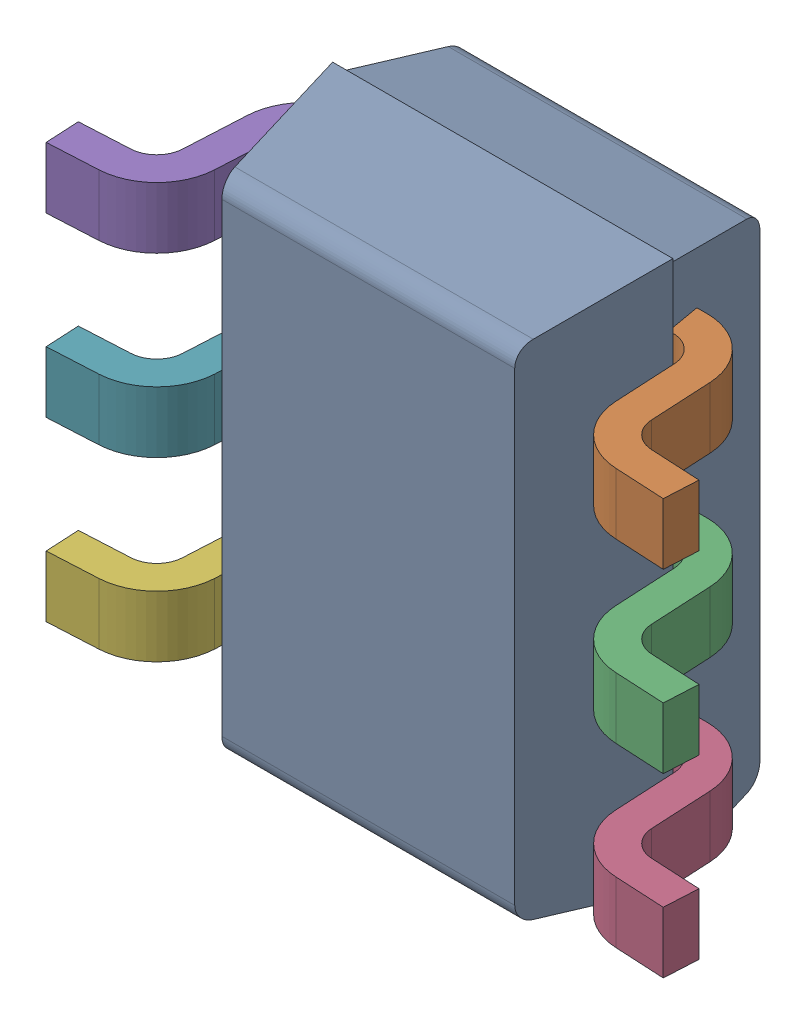
SolidWorks assembly U306_1PCB, configuration Default. Lengths in mm.
Overall size (2.28 2 0.95).
9 component instances, 7 part files, 0 mates.
Components (placement in the parent):
- DCK0006AakaMAA06-1: DCK0006AakaMAA06 [Default] at (136.7001 118.4999 -2.1938) x (0 1 0) z (1 0 0) size (2 0.95 2.28)
  - BODY_MAA06-1: BODY_MAA06 [Default] at origin size (2 0.9 1.25)
  - LEADS_MAA06-1: LEADS_MAA06 [Default] at (0.65 0 0) x (0 0 1) z (1 0 0) size (2.28 0.67 1.53)
    - LEADS_MAA06_3-1: LEADS_MAA06_3 [Default] at origin size (0.55 0.67 0.23)
    - LEADS_MAA06_4-1: LEADS_MAA06_4 [Default] at origin size (0.55 0.67 0.23)
    - LEADS_MAA06_5-1: LEADS_MAA06_5 [Default] at origin size (0.55 0.67 0.23)
    - LEADS_MAA06_6-1: LEADS_MAA06_6 [Default] at origin size (0.55 0.67 0.23)
    - LEADS_MAA06_7-1: LEADS_MAA06_7 [Default] at origin size (0.55 0.67 0.23)
    - LEADS_MAA06_8-1: LEADS_MAA06_8 [Default] at origin size (0.55 0.67 0.23)
